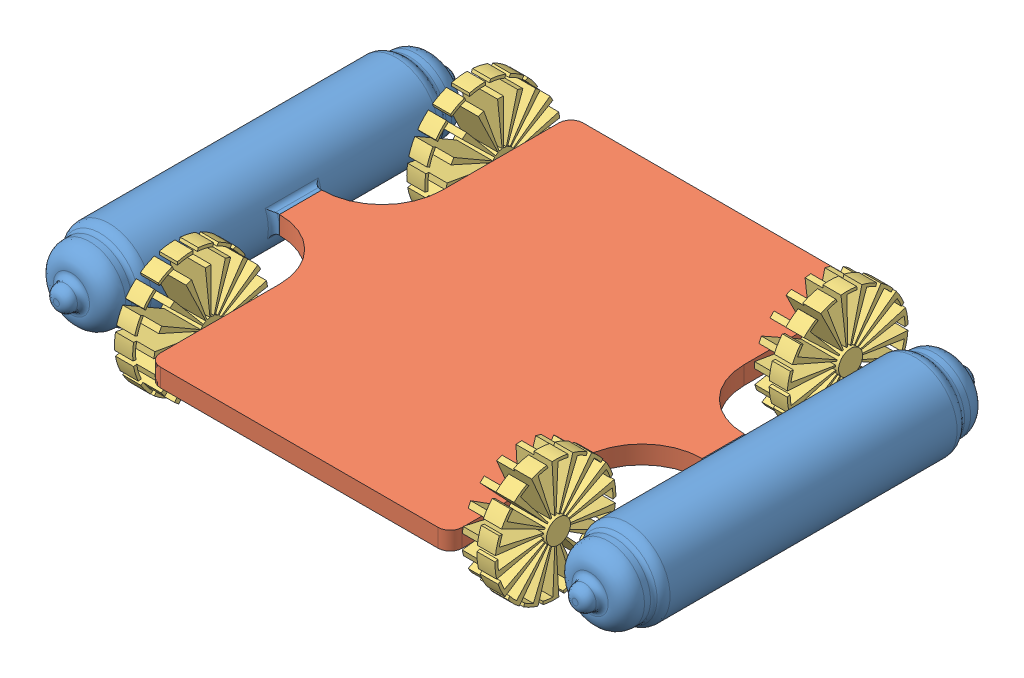
SolidWorks assembly Assieme1, configuration Default. Lengths in mm.
Overall size (998.86 263.45 726.63).
7 component instances, 3 part files, 6 mates.
Components (placement in the parent):
- Air Tank-1: Air Tank [Default] at (-63.4415 1.2515 650) size (149.43 140 650)
- Air Tank-2: Air Tank [Default] at (795.4215 1.2515 650) x (-1 0 0) z (0 0 -1) size (149.43 140 650)
- Base-1: Base [Default] at (165.4585 22.3484 980.1174) x (1 0 0) z (0 -1 0) size (700 700 30)
- Wheel-1: Wheel [Default] at (80.99 7.3484 409.2812) x (0 0 1) z (-1 0 0) size (200 200 65)
- Wheel-2: Wheel [Default] at (80.99 7.3484 893.0938) x (0 0 1) z (-1 0 0) size (200 200 65)
- Wheel-3: Wheel [Default] at (650.99 7.3484 893.0938) x (0 0.993029 -0.117873) z (1 0 0) size (200 200 65)
- Wheel-4: Wheel [Default] at (650.99 7.3484 409.2812) x (0 0.915955 -0.401282) z (1 0 0) size (200 200 65)
Mates (geometry in assembly coordinates):
- Centro profilo1: profile center anti-aligned: plane of Base-1 through (715.99 -7.6516 980.1174) normal (1 0 0); plane of Air Tank-2 through (715.99 22.3484 615) normal (-1 0 0)
- Centro profilo2: profile center anti-aligned: plane of Air Tank-1 through (15.99 22.3484 685) normal (1 0 0); plane of Base-1 through (15.99 -7.6516 980.1174) normal (-1 0 0)
- Centro profilo4: profile center anti-aligned: plane of Base-1 through (50.99 22.3484 980.1174) normal (-1 0 0); plane of Wheel-1 through (50.99 7.3484 409.2812) normal (1 0 0)
- Centro profilo5: profile center anti-aligned: plane of Base-1 through (50.99 22.3484 980.1174) normal (-1 0 0); plane of Wheel-2 through (50.99 7.3484 893.0938) normal (1 0 0)
- Centro profilo7: profile center: plane of Wheel-3 through (680.99 7.3484 893.0938) normal (-1 0 0); plane of Base-1 through (680.99 22.3484 980.1174) normal (1 0 0)
- Centro profilo8: profile center: plane of Wheel-4 through (680.99 7.3484 409.2812) normal (-1 0 0); plane of Base-1 through (680.99 22.3484 980.1174) normal (1 0 0)
